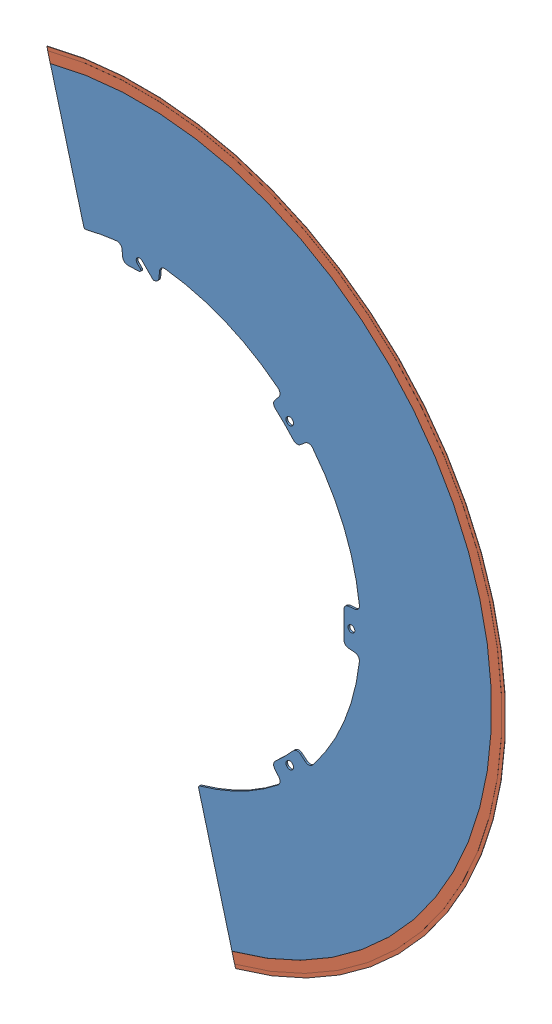
SolidWorks assembly MSC-OSC Seal, configuration Default. Lengths in mm.
Overall size (318.89 471.17 1.1).
4 component instances, 2 part files, 12 mates.
Components (placement in the parent):
- MSC-OSC Seal Plate-1: MSC-OSC Seal Plate [Default] at origin size (263.88 412.55 1)
- MSC-OSC Seal Trim-1: MSC-OSC Seal Trim [outer] at (0 0 1) x (0.965926 0.258819 0) z (0 0 1) size (212.75 426 0.05)
- MSC-OSC Seal Trim-2: MSC-OSC Seal Trim [inner] at (0 0 0.873) x (0.965926 0.258819 0) z (0 0 1) size (214.86 430.22 0.13)
- MSC-OSC Seal Trim-3: MSC-OSC Seal Trim [outer] at (0 0 -0.0508) x (0.965926 0.258819 0) z (0 0 1) size (212.75 426 0.05)
Mates (geometry in assembly coordinates):
- Coincident2: coincident aligned: plane of MSC-OSC Seal Plate-1 through (0 0 0) normal (0 0 1); plane of assembly through (0 0 0) normal (0 0 1)
- Coincident3: coincident aligned: plane of MSC-OSC Seal Plate-1 through (0 0 0) normal (1 0 0); plane of assembly through (0 0 0) normal (1 0 0)
- Coincident4: coincident aligned: plane of MSC-OSC Seal Plate-1 through (0 0 0) normal (0 1 0); plane of assembly through (0 0 0) normal (0 1 0)
- Coincident5: coincident aligned: plane of MSC-OSC Seal Trim-1; plane of MSC-OSC Seal Trim-2
- Coincident6: coincident aligned: plane of MSC-OSC Seal Trim-1; plane of MSC-OSC Seal Trim-3
- Coincident7: coincident aligned: plane of MSC-OSC Seal Trim-1; plane of MSC-OSC Seal Trim-2
- Coincident8: coincident aligned: plane of MSC-OSC Seal Trim-1; plane of MSC-OSC Seal Trim-3
- Coincident10: coincident anti-aligned: plane of MSC-OSC Seal Trim-1 through (0 0 1) normal (0 0 -1); plane of MSC-OSC Seal Trim-2 through (0 0 1) normal (0 0 1)
- Concentric1: concentric anti-aligned: cylinder of MSC-OSC Seal Plate-1 through (0 0 0) axis (0 0 1) radius 210; cylinder of MSC-OSC Seal Trim-2 through (0 0 1) axis (0 0 -1) radius 210
- Width1: width anti-aligned: plane of MSC-OSC Seal Trim-1 through (0 0 1.0508) normal (0 0 1); plane of MSC-OSC Seal Trim-3 through (0 0 -0.0508) normal (0 0 -1); plane of MSC-OSC Seal Plate-1 through (54.352 -202.8444 0) normal (0 0 -1); plane of MSC-OSC Seal Plate-1 through (54.352 -202.8444 1) normal (0 0 1)
- Parallel1: parallel aligned: plane of MSC-OSC Seal Plate-1 through (-54.1105 202.9091 0) normal (-0.965926 -0.258819 0); plane of MSC-OSC Seal Trim-2 through (-55.4331 207.845 0.873) normal (-0.965926 -0.258819 0)
- Coincident11: coincident anti-aligned: plane of MSC-OSC Seal Plate-1 through (54.352 -202.8444 1) normal (0 0 1); plane of MSC-OSC Seal Trim-1 through (0 0 1) normal (0 0 -1)
